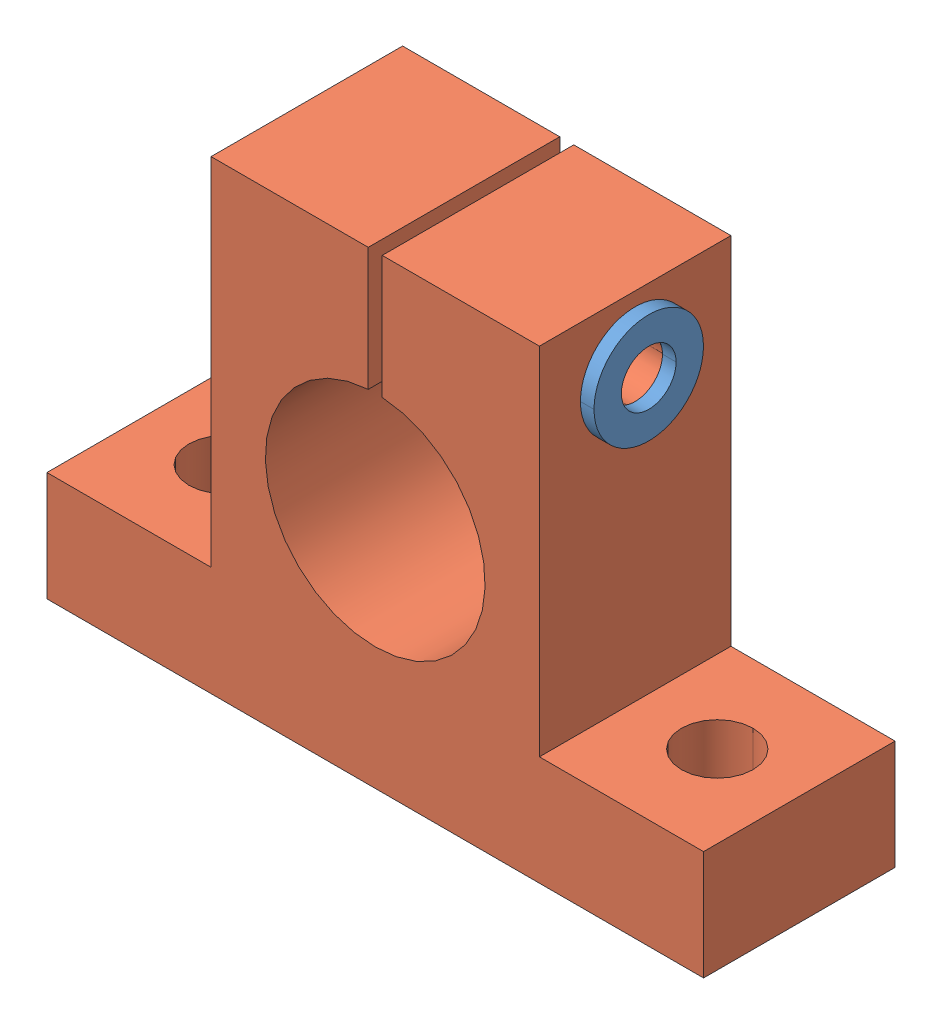
SolidWorks assembly 5370_7-TbarClamp1in, configuration Default. Lengths in mm.
Overall size (76.2 53.98 22.23).
2 component instances, 2 part files, 0 mates.
Components (placement in the parent):
- 5370_5-1: 5370_5 [Default] at (19.8374 46.0248 0) x (0 0 -1) z (-1 0 0) size (12.7 12.7 1.57)
- 5370_7-TbarClamp1in-1: 5370_7-TbarClamp1in [Default] at origin size (76.2 53.98 22.23)
